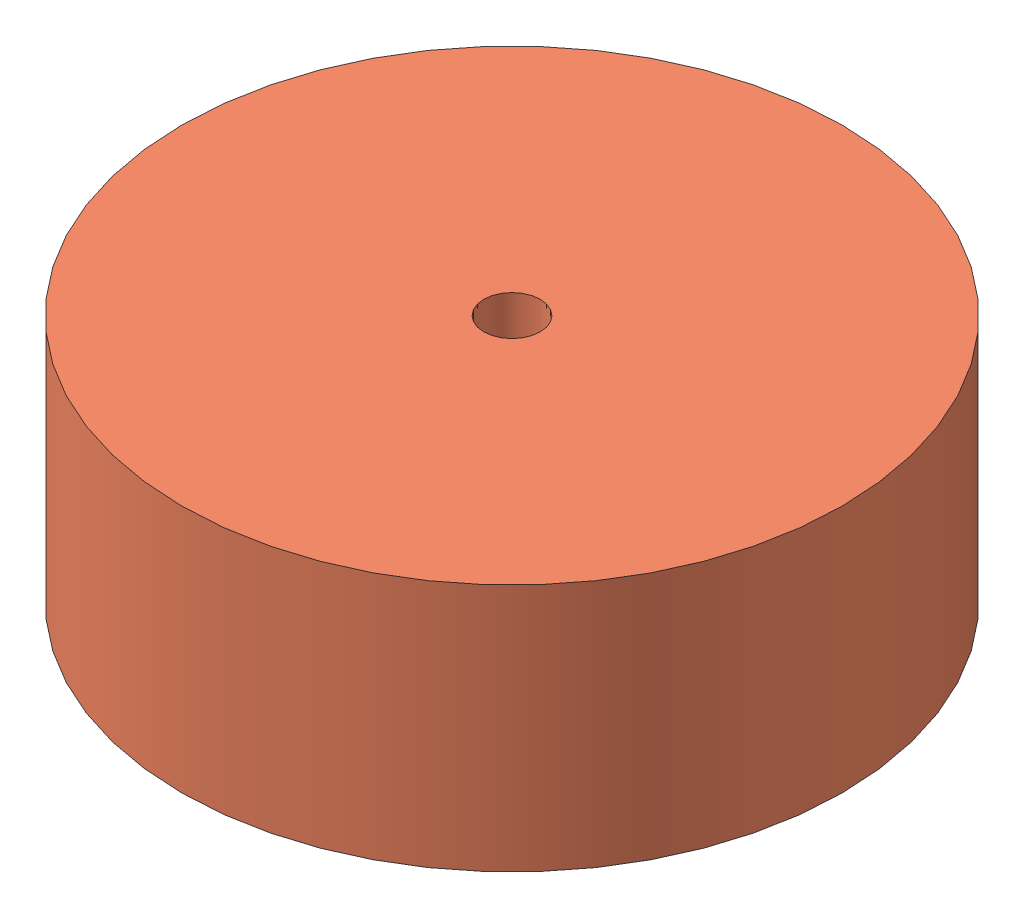
SolidWorks assembly montagem molde, configuration Valor predeterminado. Lengths in mm.
Overall size (87.39 22 87.39).
2 component instances, 2 part files, 4 mates.
Components (placement in the parent):
- roda-1: roda [Valor predeterminado] at origin size (34 15 34)
- Peça9^montagem molde-1: Peça9^montagem molde [Valor predeterminado] at (0 -4.5 0) x (1 0 0) z (0 1 0) size (58.47 58.47 22) (virtual)
Mates (geometry in assembly coordinates):
- No local1: in place: plane of roda-1 through (0 -4.5 0) normal (0 1 0); plane of Peça9^montagem molde-1 through (0 -4.5 0) normal (0 1 0); moOrthogonalPlaneRef_w of roda-1 through (0 -4.5 0) normal (0 1 0); plane of Peça9^montagem molde-1 through (0 -4.5 0) normal (0 0 -1); plane of roda-1 through (0 -4.5 0) normal (0 1 0); plane of Peça9^montagem molde-1 through (0 -4.5 0) normal (1 0 0); plane of roda-1 through (0 -4.5 0) normal (0 1 0); unknown of Peça9^montagem molde-1
- Coincidente1: coincident aligned: plane of roda-1; plane of Peça9^montagem molde-1
- Coincidente2: coincident aligned: moOrthogonalPlaneRef_w of roda-1 through (0 -4.5 0) normal (0 0 -1); plane of Peça9^montagem molde-1 through (0 -4.5 0) normal (0 0 -1)
- Coincidente3: coincident anti-aligned: moOrthogonalPlaneRef_w of roda-1 through (0 -4.5 0) normal (-1 0 0); plane of Peça9^montagem molde-1 through (0 -4.5 0) normal (1 0 0)
